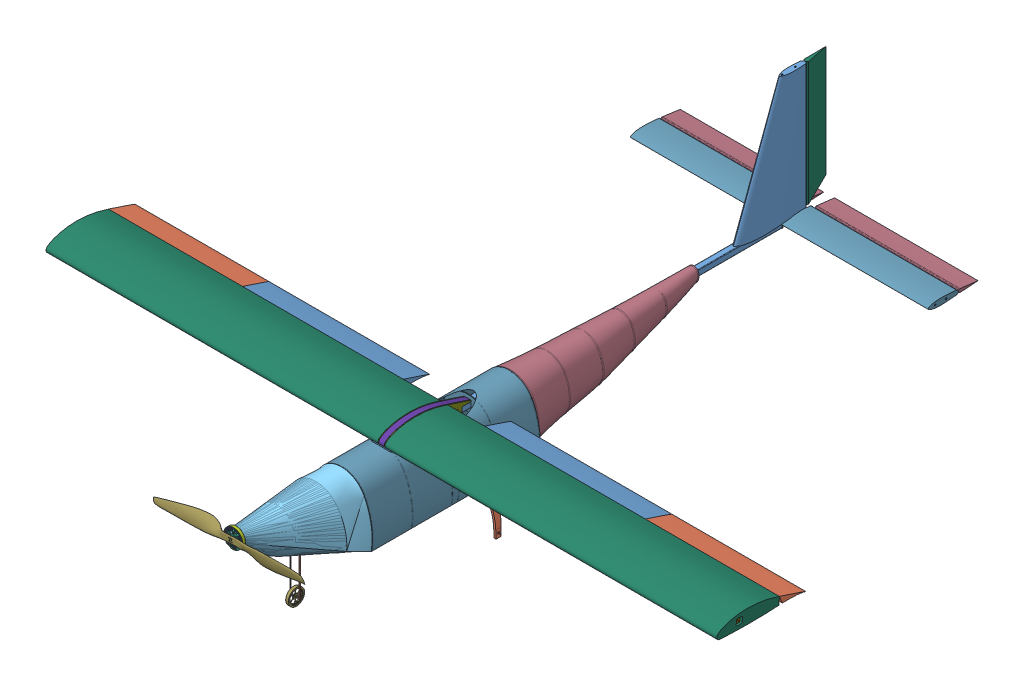
SolidWorks assembly PlaneV3.0 Assembly, configuration Default. Lengths in mm.
Overall size (3147.67 1015.53 2857.48).
66 component instances, 38 part files, 29 mates.
Components (placement in the parent):
- TailSpar-1: TailSpar [Default] at origin size (27.66 27.66 2540)
- TailGear_Assembly-2: TailGear_Assembly [Default] at (-174.2192 -572.1059 -138.9098) size (571.5 420.49 145.53)
  - TailGear-1: TailGear [Default] at (177.3942 228.0756 483.4818) x (-1 0 0) z (0 0 -1) size (546.1 279.4 41.27)
  - 2.5inWheel-1: 2.5inWheel [Default] at (456.7942 248.7131 462.8443) x (0 0 -1) z (1 0 0) size (127 127 12.7)
  - 2.5inWheel-2: 2.5inWheel [Default] at (-102.0058 248.7131 462.8443) x (0 0.158553 0.987351) z (-1 0 0) size (127 127 12.7)
  - TailGear_Boom_Mount_Sheet-1: TailGear_Boom_Mount_Sheet [Default] at (174.2192 511.6229 497.4746) size (209.56 50.86 45.89)
  - dowel pin (hardened production)_ai1-2: dowel pin (hardened production)_ai1 [ASME B18.8.2 - 0.1095x0.75] at (440.9192 248.7131 462.8443) size (19.05 2.78 2.78)
  - dowel pin (hardened production)_ai1-3: dowel pin (hardened production)_ai1 [ASME B18.8.2 - 0.1095x0.75] at (-86.1308 248.7131 462.8443) x (-1 0 0) z (0 0.984808 -0.173648) size (19.05 2.78 2.78)
  - Spacers-1: Spacers [Default] at (231.3692 507.4756 462.8443) x (-1 0 0) z (0 0 -1) size (19.05 38.1 19.05)
  - Spacers-2: Spacers [Default] at (117.0692 507.4756 462.8443) x (0 0 -1) z (1 0 0) size (19.05 38.1 19.05)
  - binding head screw_ai-2: binding head screw_ai [CR-BHMS 0.216-24x2x1.5-N] at (231.3692 551.697 462.8443) x (0 -1 0) z (-0.719741 0 0.694243) size (54.34 11.53 11.53)
  - binding head screw_ai-3: binding head screw_ai [CR-BHMS 0.216-24x2x1.5-N] at (117.0692 551.697 462.8443) x (0 -1 0) z (0.015235 0 0.999884) size (54.34 11.53 11.53)
- NG_Assembly-1: NG_Assembly [Default] at (0 -16.3195 1015.6355) x (-1 0 0) z (0 0 -1) size (50.8 434.28 103.12)
  - NG_BottomPlate-1: NG_BottomPlate [Default] at origin size (48.77 1.59 101.6)
  - NG_TopPlate-1: NG_TopPlate [Default] at (0 31.0515 0) size (48.77 1.59 101.6)
  - Shaft_SetScrew_Top-1: Shaft_SetScrew_Top [Default] at (0 -9.525 6.35) x (0.986759 0 0.162195) z (-0.162195 0 0.986759) size (38.1 28.58 38.1)
  - NG_UBracket-1: NG_UBracket [Default] at (0 -14.3256 0) size (48.77 50.8 101.6)
  - Nose_Gear-1: Nose_Gear [Default] at (0 -155.575 10.3187) size (48.33 358.78 20.71)
  - 1.5inWheel-1: 1.5inWheel [Default] at (0 -363.5375 14.22) x (0 0 1) z (-1 0 0) size (76.2 76.2 12.7)
  - dowel pin (hardened production)_ai1-1: dowel pin (hardened production)_ai1 [ASME B18.8.2 - 0.1095x2] at (25.4 -363.5375 14.22) x (-1 0 0) z (0 -0.537108 0.843513) size (50.8 2.78 2.78)
- Fairing_Asembly_OpenF-1: Fairing_Asembly_OpenF [Default] at (-62.0074 -293.3104 -255.9819) size (264.94 304.89 863.6)
- Fuselage_Assembly_ClosedF-1: Fuselage_Assembly_ClosedF [Default] at (0 -237.2254 779.547) size (290.94 274.7 787.4)
- Wing_Assembly-1: Wing_Assembly [Default] at (16.51 35.9681 596.7085) x (0 -0.052336 -0.99863) z (1 0 0) size (420.7 119.47 3147.67)
  - Wing3.0-1: Wing3.0 [Q4s] at origin size (292.27 69.24 1557.32)
  - Wing3.0-2: Wing3.0 [Q4s] at (0 0 -1590.3448) size (292.27 69.24 1557.32)
  - AirfoilBracket_Wing-1: AirfoilBracket_Wing [Default] at (1.6414 -6.403 -31.115) size (419.59 119.22 3.81)
  - AirfoilBracket_Wing-2: AirfoilBracket_Wing [Default] at (1.6414 -6.403 -1.905) size (419.59 119.22 3.81)
  - Wing_center-1: Wing_center [Q4s] at (0 0 -29.21) size (420.7 69.24 25.4)
  - WingSpar-1: WingSpar [Default] at (105.1687 18.9732 -16.51) size (27.66 27.66 3127.38)
  - HLD_Flap-1: HLD_Flap [Q4s] at (-0.0496 0.4035 174.2948) x (0.999999 -0.001381 0) z (0 0 1) size (127.04 36.12 754.38)
  - HLD_Flap-2: HLD_Flap [Q4s] at (-0.0496 0.4035 -961.6948) x (0.999999 -0.001381 0) z (0 0 1) size (127.04 36.12 754.38)
  - Aileron-1: Aileron [Default] at (-0.0699 0.57 928.6748) x (0.999998 -0.001951 0) z (0 0 1) size (127.04 36.12 628.65)
  - Aileron-2: Aileron [Default] at (-0.0699 0.57 -1590.3448) x (0.999998 -0.001951 0) z (0 0 1) size (127.04 36.12 628.65)
  - hex bolt_ai-1: hex bolt_ai [HBOLT 0.2500-28x1.5x0.75-C] at (151.203 -46.0375 4.7752) x (0 0 -1) z (1 0 0) size (42.88 12.85 11.13)
  - hex bolt_ai-2: hex bolt_ai [HBOLT 0.2500-28x1.5x0.75-C] at (49.7423 -51.3548 4.7752) x (0 0 -1) z (1 0 0) size (42.88 12.85 11.13)
  - hex bolt_ai-3: hex bolt_ai [HBOLT 0.2500-28x1.5x0.75-C] at (252.6638 -40.7202 4.7752) x (0 0 -1) z (1 0 0) size (42.88 12.85 11.13)
  - hex bolt_ai-4: hex bolt_ai [HBOLT 0.2500-28x1.5x0.75-C] at (354.1246 -35.4028 4.7752) x (0 0 -1) z (0.129381 -0.991595 0) size (42.88 12.85 11.13)
  - hex nut_ai-2: hex nut_ai [HNUT 0.2500-28-D-N] at (49.7423 -51.3548 -38.7604) x (0.923728 0.383049 0) z (0 0 -1) size (11.11 12.83 5.74)
  - hex nut_ai-3: hex nut_ai [HNUT 0.2500-28-D-N] at (151.203 -46.0375 -38.7604) x (0.923728 0.383049 0) z (0 0 -1) size (11.11 12.83 5.74)
  - hex nut_ai-4: hex nut_ai [HNUT 0.2500-28-D-N] at (354.1246 -35.4028 -38.7604) x (0.923728 0.383049 0) z (0 0 -1) size (11.11 12.83 5.74)
  - hex nut_ai-5: hex nut_ai [HNUT 0.2500-28-D-N] at (252.6638 -40.7202 -33.02) size (11.11 12.83 5.74)
- Nose Cone-1: Nose Cone [Default] at (-1.0287 -195.4403 903.732) x (1 0 0) z (0 -1 0) size (310.46 489.46 286.12)
- Motor_Assembly-1: Motor_Assembly [Default] at (148.1454 1765.1789 214.4839) x (-0.050012 0.015423 -0.99863) z (-0.294684 -0.955595 0) size (64.94 703.19 272.74)
  - ASM000_TMOTOR_U8-1: ASM000_TMOTOR_U8 [Default] at (-1076.4207 322.71 1730.4517) x (-0.041634 0.794416 -0.605945) z (0.031713 -0.605115 -0.795507) size (88.66 26.69 87.17)
    - 020_U8_STATOR_HOUSING-1: 020_U8_STATOR_HOUSING [Default] at origin size (86.8 18.69 86.8)
    - 010_U8_ROTOR-1: 010_U8_ROTOR [Default] at origin size (88.66 24.5 87.17)
    - 021_U8_STATOR_COILS-1: 021_U8_STATOR_COILS [Default] at (0 -12.5 0) size (81 11.5 81)
    - 5972K155_BALL BEARING-1: 5972K155_BALL BEARING [5972K155] at (0 -10.5 0) x (1 0 0) z (0 -1 0) size (24 24 5)
    - 5972K155_BALL BEARING-2: 5972K155_BALL BEARING [5972K155] at (0 -22 0) x (1 0 0) z (0 -1 0) size (24 24 5)
    - 011_U8_ROTOR_CAP-1: 011_U8_ROTOR_CAP [Default] at (0 -24.5 0) x (1 0 0) z (0 0 -1) size (18.5 2 18.5)
    - 91294A128_BLACK ALLOY STEEL FLAT-HEAD SOCKET CAP SCREW-1: 91294A128_BLACK ALLOY STEEL FLAT-HEAD SOCKET CAP SCREW [91294A128] at (0 -26.5 5.5) x (1 0 0) z (0 -1 0) size (6 6 8.29)
    - 91294A128_BLACK ALLOY STEEL FLAT-HEAD SOCKET CAP SCREW-2: 91294A128_BLACK ALLOY STEEL FLAT-HEAD SOCKET CAP SCREW [91294A128] at (0 -26.5 -5.5) x (0.999066 0 -0.043219) z (0 -1 0) size (6 6 8.29)
  - 28in Propellar Blade Half-1: 28in Propellar Blade Half [Default] at (-1105.8296 318.6252 1723.1608) x (-0.049422 0.943037 -0.328997) z (-0.017218 0.328546 0.944331) size (355.78 28.24 68.37)
  - 28in Propellar Blade Half-2: 28in Propellar Blade Half [Default] at (-1106.1347 323.6963 1737.7426) x (0.049422 -0.943037 0.328997) z (0.017218 -0.328546 -0.944331) size (355.78 28.24 68.37)
- Tail_Assembly-1: Tail_Assembly [Default] at (-1945.3825 -371.8016 -778.8057) x (0.000499 -0.000374 -1) z (1 -0.000259 0.000499) size (451.7 622.57 1397.12)
  - Elevator-1: Elevator [Default] at (492.122 379.2937 1582.949) x (0.998942 -0.045988 -0.000487) z (0.000499 0.00026 1) size (92.08 16.15 673.1)
  - Horizontal_stabilizer-1: Horizontal_stabilizer [Default] at (491.9754 372.5377 1589.3008) x (0.999999 0.001563 -0.0005) z (0.000499 0.00026 1) size (144.82 29.24 685.8)
  - Rudder-1: Rudder [Default] at (492.4867 969.5335 1957.573) x (0.994379 0.000345 -0.105876) z (0.000374 -1 0.000259) size (113.98 20.6 584.38)
  - Tail_attachment-1: Tail_attachment [Default] at (593.6259 372.668 1944.8501) x (0.000499 0.00026 1) z (0.000374 -1 0.000259) size (25.4 152.4 25.4)
  - Tail_cf_rod_HS-1: Tail_cf_rod_HS [Default] at (576.4486 372.8428 2643.3587) x (0.998942 -0.045988 -0.000487) z (0.045988 0.998942 -0.000282) size (7.24 1397 7.24)
  - Tail_cf_rod_VS-1: Tail_cf_rod_VS [Default] at (504.7355 347.2348 1944.9011) x (0.972062 0.000425 0.234724) z (-0.234724 0.000164 0.972062) size (7.24 622.3 7.24)
  - Vetical_Stabilizer-1: Vetical_Stabilizer [Default] at (491.8026 969.5299 1944.746) x (1 0.000374 -0.000499) z (0.000374 -1 0.000259) size (337.04 56.71 584.54)
  - Elevator-2: Elevator [Default] at (492.3655 375.9774 2306.8498) x (0.999772 -0.02133 -0.000493) z (0.000499 0.00026 1) size (92.08 16.15 673.1)
  - Horizontal_stabilizer-2: Horizontal_stabilizer [Default] at (492.3304 372.7224 2300.5007) x (0.999999 0.001563 -0.0005) z (0.000499 0.00026 1) size (144.82 29.24 685.8)
  - Tail_cf_rod_HS-2: Tail_cf_rod_HS [Default] at (525.6486 372.8238 2643.3841) x (0.998942 -0.045988 -0.000487) z (0.045988 0.998942 -0.000282) size (7.24 1397 7.24)
  - Tail_cf_rod_VS-2: Tail_cf_rod_VS [Default] at (568.2354 347.2585 1944.8694) x (0.993671 0.000401 0.112329) z (-0.11233 0.000216 0.993671) size (7.24 622.3 7.24)
Mates (geometry in assembly coordinates):
- Coincident1: coincident: plane of WingSpar-1 through (-11.2903 -13.8303 1270) normal (0 -1 0); line of TailGear_Assembly-2/TailGear_Boom_Mount_Sheet-1 through (-9.525 -13.8303 342.3434) axis (1 0 0)
- Coincident2: coincident: plane of WingSpar-1 through (-11.2903 -13.8303 1270) normal (0 -1 0); line of TailGear_Assembly-2/TailGear_Boom_Mount_Sheet-1 through (-9.525 -13.8303 305.5256) axis (1 0 0)
- Width1: width anti-aligned: plane of TailSpar-1 through (13.8303 11.2903 1270) normal (1 0 0); plane of TailSpar-1 through (-13.8303 11.2903 1270) normal (-1 0 0); plane of TailGear_Assembly-2/TailGear_Boom_Mount_Sheet-1 through (14.605 -13.0219 342.3857) normal (-1 0 0); plane of TailGear_Assembly-2/TailGear_Boom_Mount_Sheet-1 through (-14.605 23.6711 344.3087) normal (1 0 0)
- Parallel1: parallel anti-aligned: plane of NG_Assembly-1 through (0 -16.3195 1015.6355) normal (0 0 -1)
- Width2: width anti-aligned: plane of TailSpar-1 through (-11.2903 13.8303 1270) normal (0 1 0); plane of NG_Assembly-1/NG_TopPlate-1 through (-11.2903 -13.8303 1270) normal (0 -1 0); plane of TailSpar-1 through (0 14.732 1015.6355) normal (0 -1 0); plane of NG_Assembly-1/NG_BottomPlate-1 through (0 -14.732 1015.6355) normal (0 1 0)
- Width3: width anti-aligned: plane of NG_Assembly-1/NG_UBracket-1 through (24.384 -30.6451 964.8355) normal (1 0 0); plane of TailSpar-1 through (-24.384 -30.6451 964.8355) normal (-1 0 0); plane of NG_Assembly-1/NG_UBracket-1 through (-13.8303 11.2903 1270) normal (-1 0 0); plane of TailSpar-1 through (13.8303 11.2903 1270) normal (1 0 0)
- Coincident4: coincident anti-aligned: plane of WingSpar-1 through (-11.2903 -13.8303 1270) normal (0 -1 0); plane of Fairing_Asembly_OpenF-1 through (9.525 -13.8303 -11.028) normal (0 1 0)
- Width4: width anti-aligned: plane of Fairing_Asembly_OpenF-1 through (14.605 10.2997 -11.028) normal (-1 0 0); plane of TailSpar-1 through (-14.605 -8.7503 -11.028) normal (1 0 0); plane of Fairing_Asembly_OpenF-1 through (13.8303 11.2903 1270) normal (1 0 0); plane of TailSpar-1 through (-13.8303 11.2903 1270) normal (-1 0 0)
- Coincident7: coincident anti-aligned: plane of TailSpar-1 through (-11.2903 -13.8303 1270) normal (0 -1 0); plane of Fuselage_Assembly_ClosedF-1 through (12.319 -13.8303 779.547) normal (0 1 0)
- Width6: width anti-aligned: plane of Fuselage_Assembly_ClosedF-1 through (-14.859 -11.2903 779.547) normal (1 0 0); plane of TailSpar-1 through (14.859 13.3477 779.547) normal (-1 0 0); plane of Fuselage_Assembly_ClosedF-1 through (-13.8303 11.2903 1270) normal (-1 0 0); plane of TailSpar-1 through (13.8303 11.2903 1270) normal (1 0 0)
- Distance2: distance = 304.8 mm anti-aligned: plane of Fuselage_Assembly_ClosedF-1 through (0 -237.2254 -1.503) normal (0 0 1); line of TailGear_Assembly-2/TailGear-1 through (-102.8167 -64.6303 303.297) axis (1 0 0)
- Width7: width anti-aligned: plane of Wing_Assembly-1/AirfoilBracket_Wing-1 through (-12.7 52.8845 291.3219) normal (1 0 0); plane of TailSpar-1 through (12.7 52.8845 291.3219) normal (-1 0 0); plane of Wing_Assembly-1/AirfoilBracket_Wing-2 through (-13.8303 11.2903 1270) normal (-1 0 0); plane of TailSpar-1 through (13.8303 11.2903 1270) normal (1 0 0)
- Coincident10: coincident anti-aligned: plane of TailSpar-1 through (-11.2903 13.8303 1270) normal (0 1 0); plane of Wing_Assembly-1/AirfoilBracket_Wing-2 through (16.51 13.8303 595.4045) normal (0 -1 0)
- Distance4: distance = 812.8 mm: point of Wing_Assembly-1/Wing3.0-1; plane of TailSpar-1 through (-11.2903 -11.2903 1270) normal (0 0 1)
- Coincident13: coincident: plane of Fuselage_Assembly_ClosedF-1 through (0 -237.2254 595.397) normal (0 0 1); moEndPointRef_w of Wing_Assembly-1/Wing3.0-1
- Coincident14: coincident anti-aligned: plane of Fairing_Asembly_OpenF-1 through (-26.0068 -105.604 -4.678) normal (0 0 1); plane of Fuselage_Assembly_ClosedF-1 through (0 -237.2254 -4.678) normal (0 0 -1)
- Parallel4: parallel aligned: plane of Nose Cone-1 through (-1.0287 -195.4403 903.732) normal (0 0 1)
- Coincident18: coincident anti-aligned: plane of TailSpar-1 through (-11.2903 -11.2903 1270) normal (0 0 1); plane of Nose Cone-1 through (18.3521 -31.0183 1270) normal (0 0 -1)
- Coincident19: coincident: plane of TailSpar-1 through (-11.2903 -13.8303 1270) normal (0 -1 0); line of Nose Cone-1 through (11.2903 -13.8303 903.732) axis (-1 0 0)
- Coincident20: coincident: plane of TailSpar-1 through (13.8303 11.2903 1270) normal (1 0 0); line of Nose Cone-1 through (13.8303 13.3477 903.732) axis (0 -1 0)
- Coincident21: coincident anti-aligned: plane of 28in Propellar Blade Half-1 through (-1472.3461 -62.6613 2737.1347) normal (0.052333 -0.998578 0.010123); plane of 28in Propellar Blade Half-2 through (-1472.3935 -62.5073 2752.5753) normal (-0.052333 0.998578 -0.010123)
- Concentric1: concentric aligned: cylinder of 28in Propellar Blade Half-1 through (-1467.357 -62.3216 2744.855) axis (-0.99863 -0.052336 0) radius 5; cylinder of 28in Propellar Blade Half-2 through (-1467.3963 -62.3236 2744.855) axis (-0.99863 -0.052336 0) radius 5
- Tangent3: tangent: plane of Motor_Assembly-1/ASM000_TMOTOR_U8-1/010_U8_ROTOR-1 through (18.7749 6.8923 1272.54) normal (0 0 -1); curve of Nose Cone-1
- Tangent4: tangent: curve of Nose Cone-1; plane of Motor_Assembly-1/ASM000_TMOTOR_U8-1/010_U8_ROTOR-1 through (18.7749 6.8923 1272.54) normal (0 0 -1)
- Width8: width: plane of TailSpar-1 through (-12.5603 11.2903 1270) normal (1 0 0); plane of Motor_Assembly-1/ASM000_TMOTOR_U8-1/010_U8_ROTOR-1 through (12.5603 11.2903 1270) normal (-1 0 0); cylinder of TailSpar-1 through (0 0 1272.54) axis (0 0 -1) radius 43.4
- Width9: width: plane of TailSpar-1 through (-11.2903 12.5603 1270) normal (0 -1 0); plane of Motor_Assembly-1/ASM000_TMOTOR_U8-1/010_U8_ROTOR-1 through (-11.2903 -12.5603 1270) normal (0 1 0); cylinder of TailSpar-1 through (0 0 1272.54) axis (0 0 -1) radius 43.4
- Coincident24: coincident anti-aligned: plane of TailSpar-1 through (-11.2903 -12.5603 1270) normal (0 1 0); plane of Tail_Assembly-1/Tail_attachment-1 through (-7.7597 -12.5603 -1219.2) normal (0 -1 0)
- Coincident25: coincident anti-aligned: plane of TailSpar-1 through (12.5603 11.2903 1270) normal (-1 0 0); plane of Tail_Assembly-1/Tail_attachment-1 through (12.5603 7.7597 -1219.2) normal (1 0 0)
- Distance5: distance = 50.8 mm anti-aligned: plane of TailSpar-1 through (-11.2903 -11.2903 -1270) normal (0 0 -1); plane of Tail_Assembly-1/Tail_attachment-1 through (-7.7597 -7.4803 -1219.2) normal (0 0 1)
